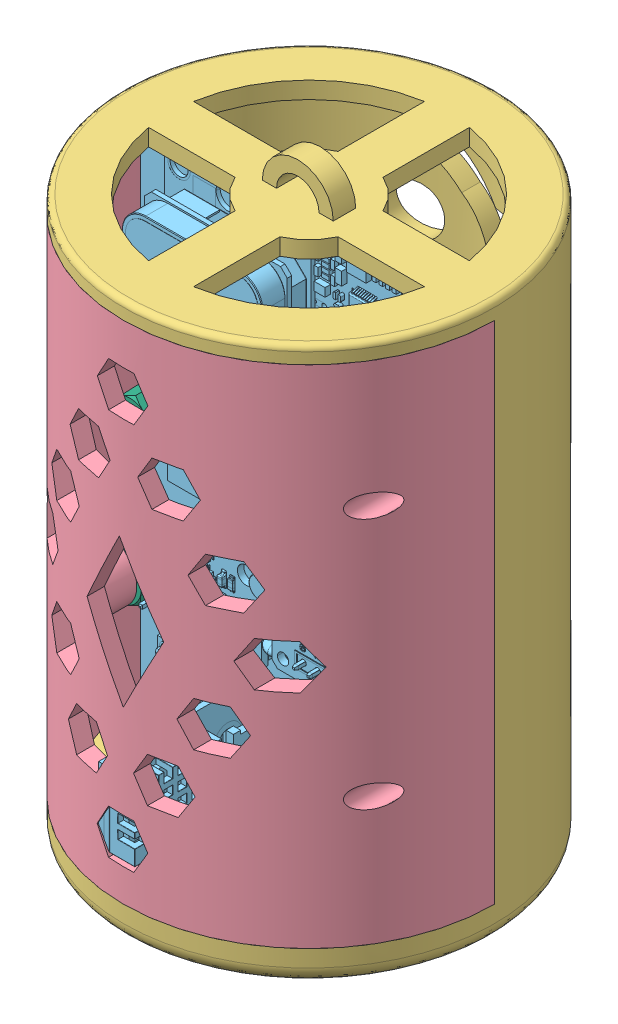
SolidWorks assembly Assem1, configuration Default. Lengths in mm.
Overall size (68.71 105.32 66).
11 component instances, 6 part files, 36 mates.
Components (placement in the parent):
- 9V BATTERY-1: 9V BATTERY [Default] at (-7.5 -70.5 -18) size (25 47 15)
- Battery Cover -1: Battery Cover  [Default] at (-5.9311 -92 -14.7327) x (-1 0 0) z (0 0 -1) size (29 52 30)
- Fixed Part (3)-1: Fixed Part (3) [Default] x (-1 0 0) z (0 0 -1) size (66 105.32 66)
- Movable Part-1: Movable Part [Default] at (0 -90 0) x (-1 0 0) z (0 0 -1) size (66 90 34.89)
- OBTIMIZED printing-1: OBTIMIZED printing [Default] at (30.7372 -89.5 0) x (0 1 0) z (0 0 1) size (93.91 61.5 56.19)
- hex cap screw_am-1: hex cap screw_am [B18.2.3.1M - Hex cap screw, M5 x 0.8 x 10 --10C] at (28.2372 -44.75 3.65) x (0 0 -1) z (0.625351 0.780343 0) size (13.65 9.24 8)
- hex cap screw_am-4: hex cap screw_am [B18.2.3.1M - Hex cap screw, M5 x 0.8 x 10 --10C] at (-28.2628 -44.75 3.65) x (0 0 -1) z (0.625351 0.780343 0) size (13.65 9.24 8)
- hex cap screw_am-5: hex cap screw_am [B18.2.3.1M - Hex cap screw, M5 x 0.8 x 10 --10C] at (-28.2 -22.4 5.65) x (0 0 -1) z (0.625351 0.780343 0) size (13.65 9.24 8)
- hex cap screw_am-7: hex cap screw_am [B18.2.3.1M - Hex cap screw, M5 x 0.8 x 10 --10C] at (28.2 -22.4 5.65) x (0 0 -1) z (0.625351 0.780343 0) size (13.65 9.24 8)
- hex cap screw_am-8: hex cap screw_am [B18.2.3.1M - Hex cap screw, M5 x 0.8 x 10 --10C] at (28.2 -67.2 5.65) x (0 0 -1) z (0.625351 0.780343 0) size (13.65 9.24 8)
- hex cap screw_am-9: hex cap screw_am [B18.2.3.1M - Hex cap screw, M5 x 0.8 x 10 --10C] at (-28.2 -67.2 5.65) x (0 0 -1) z (0.625351 0.780343 0) size (13.65 9.24 8)
Mates (geometry in assembly coordinates):
- Coincident10: coincident anti-aligned: plane of Fixed Part (3)-1 through (30.7372 -90 0) normal (-1 0 0); plane of OBTIMIZED printing-1 through (30.7372 -89.5 0) normal (1 0 0)
- Coincident11: coincident anti-aligned: plane of Fixed Part (3)-1 through (0 0 0) normal (0 -1 0); plane of OBTIMIZED printing-1 through (30.7372 0 0) normal (0 1 0)
- Parallel3: parallel anti-aligned: line of Fixed Part (3)-1 through (-30.7372 -90 0) axis (0 1 0); line of OBTIMIZED printing-1 through (-30.7628 0 0) axis (0 -1 0)
- Coincident13: coincident aligned: line of Fixed Part (3)-1 through (30.7372 -90 0) axis (0 1 0); line of OBTIMIZED printing-1 through (30.7372 -89.5 0) axis (0 1 0)
- Concentric5: concentric aligned: cylinder of OBTIMIZED printing-1 through (28.2372 -44.75 0) axis (0 0 1) radius 1; cylinder of hex cap screw_am-1 through (28.2372 -44.75 3.65) axis (0 0 1) radius 2.5
- Coincident15: coincident anti-aligned: plane of OBTIMIZED printing-1 through (30.7372 -89.5 0) normal (0 0 1); plane of hex cap screw_am-1 through (24.633 -41.8616 0) normal (0 0 -1)
- Concentric8: concentric aligned: cylinder of OBTIMIZED printing-1 through (-28.2628 -44.75 0) axis (0 0 1) radius 1; cylinder of hex cap screw_am-4 through (-28.2628 -44.75 3.65) axis (0 0 1) radius 2.5
- Coincident18: coincident anti-aligned: plane of OBTIMIZED printing-1 through (30.7372 -89.5 0) normal (0 0 1); plane of hex cap screw_am-4 through (-31.867 -41.8616 0) normal (0 0 -1)
- Coincident19: coincident anti-aligned: plane of Fixed Part (3)-1 through (33 -90 0) normal (0 0 1); plane of Movable Part-1 through (30 0 0) normal (0 0 -1)
- Coincident20: coincident anti-aligned: plane of Fixed Part (3)-1 through (0 -90 0) normal (0 1 0); plane of Movable Part-1 through (0 -90 0) normal (0 -1 0)
- Coincident21: coincident aligned: circle of Fixed Part (3)-1; circle of Movable Part-1
- Concentric9: concentric anti-aligned: cylinder of Movable Part-1 through (-28.2 -22.4 25) axis (0 0 -1) radius 2; cylinder of hex cap screw_am-5 through (-28.2 -22.4 5.65) axis (0 0 1) radius 2.5
- Coincident22: coincident anti-aligned: plane of Movable Part-1 through (-28.2 -22.4 2) normal (0 0 1); plane of hex cap screw_am-5 through (-31.8043 -19.5116 2) normal (0 0 -1)
- Concentric11: concentric anti-aligned: cylinder of Movable Part-1 through (28.2 -22.4 25) axis (0 0 -1) radius 2; cylinder of hex cap screw_am-7 through (28.2 -22.4 5.65) axis (0 0 1) radius 2.5
- Coincident23: coincident anti-aligned: plane of Movable Part-1 through (28.2 -22.4 2) normal (0 0 1); plane of hex cap screw_am-7 through (24.5957 -19.5116 2) normal (0 0 -1)
- Concentric12: concentric aligned: cylinder of Movable Part-1 through (28.2 -67.2 -10) axis (0 0 1) radius 1; cylinder of hex cap screw_am-8 through (28.2 -67.2 5.65) axis (0 0 1) radius 2.5
- Coincident24: coincident anti-aligned: plane of Movable Part-1 through (28.2 -67.2 2) normal (0 0 1); plane of hex cap screw_am-8 through (24.5957 -64.3116 2) normal (0 0 -1)
- Concentric13: concentric aligned: cylinder of Movable Part-1 through (-28.2 -67.2 -10) axis (0 0 1) radius 1; cylinder of hex cap screw_am-9 through (-28.2 -67.2 5.65) axis (0 0 1) radius 2.5
- Coincident25: coincident anti-aligned: plane of Movable Part-1 through (-28.2 -67.2 2) normal (0 0 1); plane of hex cap screw_am-9 through (-31.8043 -64.3116 2) normal (0 0 -1)
- Coincident26: coincident anti-aligned: plane of Battery Cover -1 through (0 -92 0) normal (0 -1 0); plane of Fixed Part (3)-1 through (9 -92 -3) normal (0 1 0)
- Coincident28: coincident anti-aligned: circle of Battery Cover -1; circle of Fixed Part (3)-1
- Coincident29: coincident anti-aligned: plane of Battery Cover -1 through (9 -40 -3) normal (1 0 0); plane of Fixed Part (3)-1 through (9 -92 -3) normal (-1 0 0)
- Coincident32: coincident anti-aligned: plane of 9V BATTERY-1 through (-7.5 -92 -18) normal (0 -1 0); plane of Fixed Part (3)-1 through (9 -92 -3) normal (0 1 0)
- Coincident33: coincident anti-aligned: plane of 9V BATTERY-1 through (-7.5 -70.5 -3) normal (0 0 1); plane of Fixed Part (3)-1 through (0 0 -3) normal (0 0 -1)
- Parallel4: parallel aligned: line of 9V BATTERY-1 through (5 -48.5 -3.5) axis (0 -1 0); line of Fixed Part (3)-1 through (9 -90 -3) axis (0 -1 0)
- Coincident35: coincident anti-aligned: plane of 9V BATTERY-1 through (-20 -48 -3) normal (-1 0 0); plane of Fixed Part (3)-1 through (-20 -92 -3) normal (1 0 0)
- Parallel5: parallel aligned: plane of Battery Cover -1 through (-5.9311 -92 -14.7327) normal (0 0 -1); plane of Fixed Part (3)-1 through (0 0 0) normal (0 0 -1)
- Coincident39: coincident anti-aligned: plane of Fixed Part (3)-1 through (0 0 0) normal (0 0 -1)
- Coincident40: coincident aligned: plane of Fixed Part (3)-1 through (0 0 0) normal (0 1 0)
- Coincident41: coincident anti-aligned: plane of Fixed Part (3)-1 through (0 0 0) normal (-1 0 0)
- Coincident42: coincident anti-aligned: plane of Fixed Part (3)-1 through (0 0 0) normal (0 0 -1)
- Coincident43: coincident aligned: plane of Fixed Part (3)-1 through (0 0 0) normal (0 1 0)
- Coincident44: coincident anti-aligned: plane of Fixed Part (3)-1 through (0 0 0) normal (-1 0 0)
- Coincident45: coincident anti-aligned: plane of Fixed Part (3)-1 through (0 0 0) normal (0 0 -1)
- Coincident46: coincident aligned: plane of Fixed Part (3)-1 through (0 0 0) normal (0 1 0)
- Coincident47: coincident anti-aligned: plane of Fixed Part (3)-1 through (0 0 0) normal (-1 0 0)
